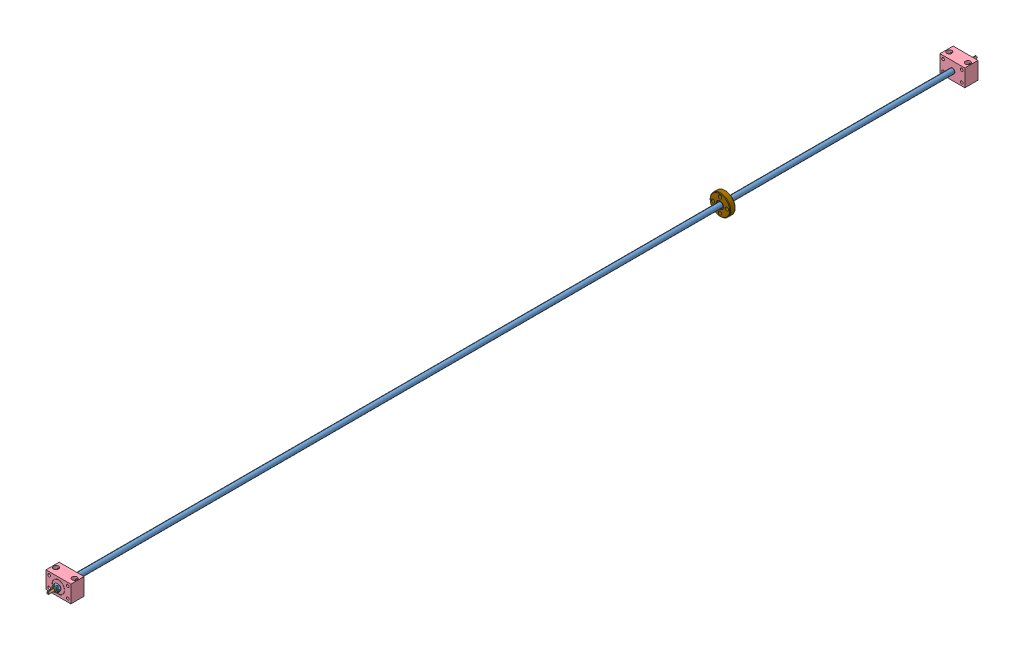
SolidWorks assembly 900_RA_EK_EK_1800_20900_FS, configuration Valor predeterminado. Lengths in mm.
Overall size (50.8 42 1898.55).
15 component instances, 9 part files, 7 mates.
Components (placement in the parent):
- Screw_900-RA-1: Screw_900-RA [Valor predeterminado] at origin size (10 10 1800)
- EndCode1_7-EK-1: EndCode1_7-EK [Valor predeterminado] at (0 0 1800) x (0 0 1) z (-1 0 0) size (49.28 35.05 50.8)
  - Place Holder-1: Place Holder [Valor predeterminado] at origin size (0.38 0.51 0.51)
  - EndMachining_7-3K-1: EndMachining_7-3K [Valor predeterminado] x (0 0 1) z (-1 0 0) size (7 7 49.28)
  - EZM_EZM-1007-1: EZM_EZM-1007 [Valor predeterminado] at (27.305 -17.4498 25.4) x (0 0 -1) z (1 0 0) size (50.8 35.05 26.92)
  - LockNut(1)_N-00.7-1: LockNut(1)_N-00.7 [Valor predeterminado] at (28.8798 0 0) x (1 0 0) z (0 0.998865 0.047634) size (7.05 16.48 14.68)
  - Spacer-1: Spacer [Valor predeterminado] at origin size (28.88 9.91 9.91)
- EndCode2_7-EK-1: EndCode2_7-EK [Valor predeterminado] x (0 0 -1) z (1 0 0) size (49.28 35.05 50.8)
  - Place Holder-1: Place Holder [Valor predeterminado] at origin size (0.38 0.51 0.51)
  - EndMachining_7-3K-1: EndMachining_7-3K [Valor predeterminado] x (0 0 1) z (-1 0 0) size (7 7 49.28)
  - EZM_EZM-1007-1: EZM_EZM-1007 [Valor predeterminado] at (27.305 -17.4498 25.4) x (0 0 -1) z (1 0 0) size (50.8 35.05 26.92)
  - LockNut(1)_N-00.7-1: LockNut(1)_N-00.7 [Valor predeterminado] at (28.8798 0 0) x (1 0 0) z (0 0.998865 0.047634) size (7.05 16.48 14.68)
  - Spacer2-1: Spacer2 [Valor predeterminado] at origin size (28.88 9.91 9.91)
- Nut_20900-1: Nut_20900 [Valor predeterminado] at (0 0 428.4213) x (-1 0 0) z (0 0 -1) size (18 18 16)
- Flange_72001-1: Flange_72001 [Valor predeterminado] at (0 0 474.8662) x (0 0 -1) z (1 0 0) size (11 42 42)
Mates (geometry in assembly coordinates):
- Concêntrico1: concentric aligned: cylinder of Screw_900-RA-1 through (0 0 1800) axis (0 0 -1) radius 5; cylinder of Nut_20900-1 through (0 0 457.8662) axis (0 0 -1) radius 4.5
- Concêntrico3: concentric anti-aligned: cylinder of Screw_900-RA-1 through (0 0 1800) axis (0 0 -1) radius 5; cylinder of Flange_72001-1 through (0 0 463.8662) axis (0 0 1) radius 7.5
- Coincidente1: coincident anti-aligned: plane of Nut_20900-1 through (0 9 463.8662) normal (0 0 1); plane of Flange_72001-1 through (0 0 463.8662) normal (0 0 -1)
- Coincidente5: coincident anti-aligned: plane of Screw_900-RA-1 through (5 0 1800) normal (0 0 1); plane of EndCode1_7-EK-1/EndMachining_7-3K-1 through (0 0 1800) normal (0 0 -1)
- Concêntrico6: concentric aligned: cylinder of Screw_900-RA-1 through (0 0 1800) axis (0 0 -1) radius 5; cylinder of EndCode1_7-EK-1/Spacer-1 through (0 0 1828.8798) axis (0 0 -1) radius 4.953
- Coincidente6: coincident anti-aligned: plane of Screw_900-RA-1 through (0 0 0) normal (0 0 -1); plane of EndCode2_7-EK-1/EndMachining_7-3K-1 through (0 0 0) normal (0 0 1)
- Concêntrico7: concentric anti-aligned: cylinder of Screw_900-RA-1 through (0 0 1800) axis (0 0 -1) radius 5; cylinder of EndCode2_7-EK-1/Spacer2-1 through (0 0 -28.8798) axis (0 0 1) radius 4.953
